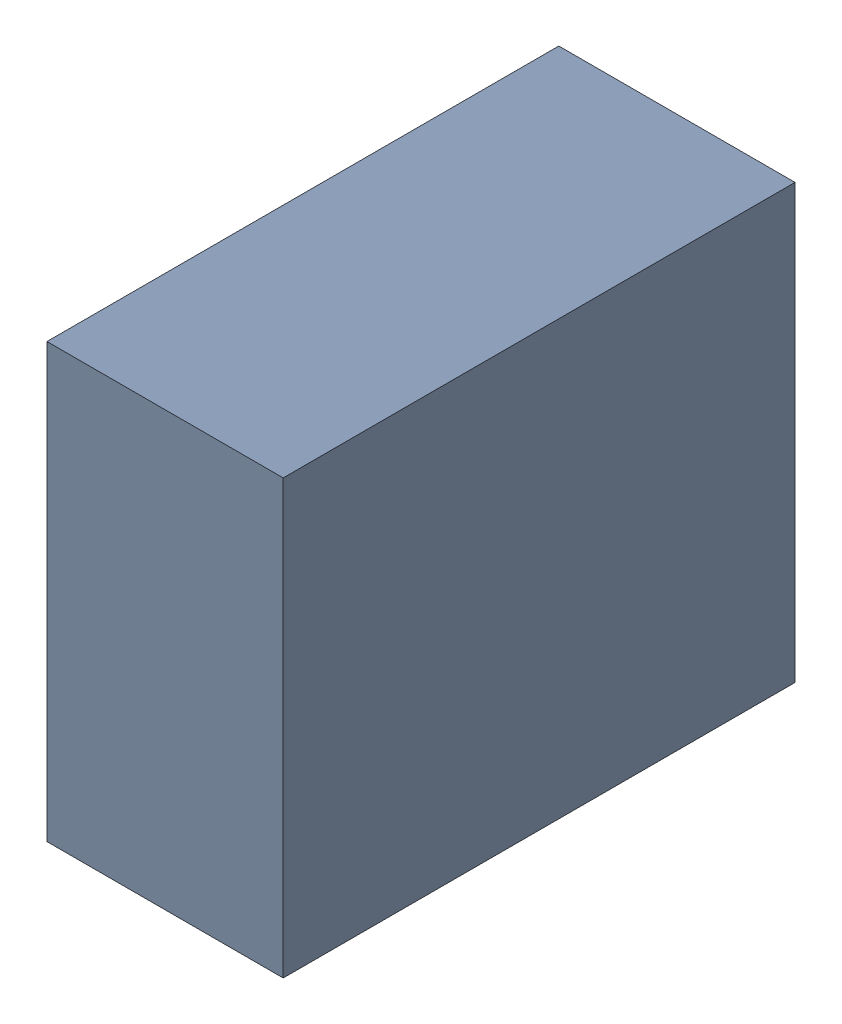
SolidWorks assembly C27_TDA4, configuration Standard. Lengths in mm.
Overall size (0.6 1.1 1.3).
2 component instances, 1 part files, 0 mates.
Components (placement in the parent):
- 885542376-1: 885542376 [Standard] at (-1.52 -57.59 0) size (0.6 1.1 1.3)
  - Extruded_25-1: Extruded_25 [Standard] at origin size (0.6 1.1 1.3)
